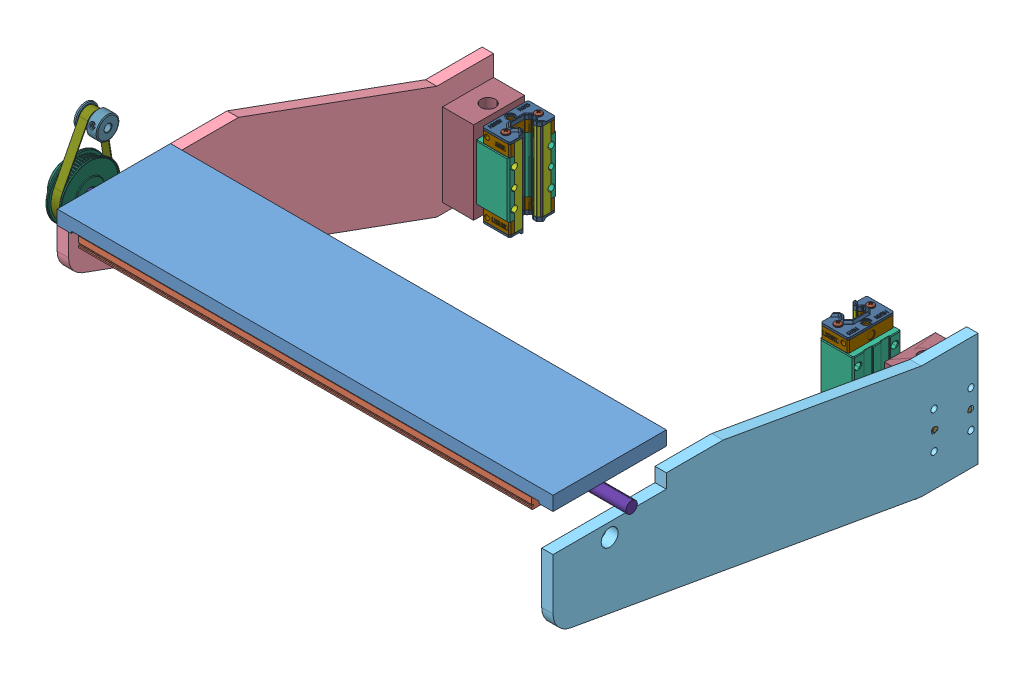
SolidWorks assembly Copia de Eje_X^Fresa_190502_2022, configuration Predeterminado. Lengths in mm.
Overall size (400 162.38 300).
39 component instances, 17 part files, 36 mates.
Components (placement in the parent):
- Puente_X-1: Puente_X [Predeterminado] at (-189.2038 15.372 -72.2278) x (1 0 0) z (0 -1 0) size (350 80 10)
- Rail_sup-1: Rail_sup [Predeterminado] at (-104.2038 2.9226 1.7722) x (0 0 1) z (1 0 0) size (12 8.1 320)
- Rail_Inf-1: Rail_Inf [Predeterminado] at (75.7962 2.9226 -66.2278) x (0 0 -1) z (-1 0 0) size (12 8.1 320)
-  Columa_xn-1:  Columa_xn [Predeterminado] at (-181.2038 -35.5839 -292.2278) x (0 -1 0) z (-1 0 0) size (130.96 300 8)
- Columa_xp-1: Columa_xp [Predeterminado] at (160.7962 -35.5839 -292.2278) x (0 -1 0) z (-1 0 0) size (130.96 300 8)
- HGH15CA-1: HGH15CA [Default] at (-131.2038 -79.3839 -274.2278) x (0 0 -1) z (0 1 0) size (34 23.7 61.49)
  - Copia de Copia de HGH15CA Block-1: Copia de Copia de HGH15CA Block [HGR15R300CE20] at origin size (34 23.7 39.4)
  - Copia de Copia de HGx15CA Retainer-1: Copia de Copia de HGx15CA Retainer [HGR15R300CE20] at origin size (26 4 55.4)
  - Copia de Copia de HGx15CA Tiny Red-1: Copia de Copia de HGx15CA Tiny Red [HGR15R300CE20] at origin size (14.2 1 55.4)
  - Copia de Copia de HGx15CA End Cap-1: Copia de Copia de HGx15CA End Cap [HGR15R300CE20] at origin size (32.5 19.5 8)
  - Copia de Copia de HGx15CA End Cap-2: Copia de Copia de HGx15CA End Cap [HGR15R300CE20] x (-1 0 0) z (0 0 -1) size (32.5 19.5 8)
  - Copia de Copia de HGx15CA Seal-1: Copia de Copia de HGx15CA Seal [HGR15R300CE20] at origin size (32.5 19.5 3)
  - Copia de Copia de HGx15CA Seal-2: Copia de Copia de HGx15CA Seal [HGR15R300CE20] x (-1 0 0) z (0 0 -1) size (32.5 19.5 3)
  - pan head cross recess screw_isog-1: pan head cross recess screw_isog [ISO 7045 - M2.5 x 16 - Z - 16C] at (11.5 11.8 30.8) x (0 0 -1) z (0 -1 0) size (18.05 5 5)
  - pan head cross recess screw_isog-2: pan head cross recess screw_isog [ISO 7045 - M2.5 x 16 - Z - 16C] at (-11.5 11.8 30.8) x (0 0 -1) z (0 1 0) size (18.05 5 5)
  - pan head cross recess screw_isog-3: pan head cross recess screw_isog [ISO 7045 - M2.5 x 16 - Z - 16C] at (11.5 11.8 -30.8) x (0 0 1) z (0 -1 0) size (18.05 5 5)
  - pan head cross recess screw_isog-4: pan head cross recess screw_isog [ISO 7045 - M2.5 x 16 - Z - 16C] at (-11.5 11.8 -30.8) x (0 0 1) z (0 1 0) size (18.05 5 5)
- HGH15CA-2: HGH15CA [Default] at (79.6902 -79.3839 -274.2278) x (0 0 -1) z (0 -1 0) size (34 23.7 61.49)
  - Copia de Copia de HGH15CA Block-1: Copia de Copia de HGH15CA Block [HGR15R300CE20] at origin size (34 23.7 39.4)
  - Copia de Copia de HGx15CA Retainer-1: Copia de Copia de HGx15CA Retainer [HGR15R300CE20] at origin size (26 4 55.4)
  - Copia de Copia de HGx15CA Tiny Red-1: Copia de Copia de HGx15CA Tiny Red [HGR15R300CE20] at origin size (14.2 1 55.4)
  - Copia de Copia de HGx15CA End Cap-1: Copia de Copia de HGx15CA End Cap [HGR15R300CE20] at origin size (32.5 19.5 8)
  - Copia de Copia de HGx15CA End Cap-2: Copia de Copia de HGx15CA End Cap [HGR15R300CE20] x (-1 0 0) z (0 0 -1) size (32.5 19.5 8)
  - Copia de Copia de HGx15CA Seal-1: Copia de Copia de HGx15CA Seal [HGR15R300CE20] at origin size (32.5 19.5 3)
  - Copia de Copia de HGx15CA Seal-2: Copia de Copia de HGx15CA Seal [HGR15R300CE20] x (-1 0 0) z (0 0 -1) size (32.5 19.5 3)
  - pan head cross recess screw_isog-1: pan head cross recess screw_isog [ISO 7045 - M2.5 x 16 - Z - 16C] at (11.5 11.8 30.8) x (0 0 -1) z (0 -1 0) size (18.05 5 5)
  - pan head cross recess screw_isog-2: pan head cross recess screw_isog [ISO 7045 - M2.5 x 16 - Z - 16C] at (-11.5 11.8 30.8) x (0 0 -1) z (0 1 0) size (18.05 5 5)
  - pan head cross recess screw_isog-3: pan head cross recess screw_isog [ISO 7045 - M2.5 x 16 - Z - 16C] at (11.5 11.8 -30.8) x (0 0 1) z (0 -1 0) size (18.05 5 5)
  - pan head cross recess screw_isog-4: pan head cross recess screw_isog [ISO 7045 - M2.5 x 16 - Z - 16C] at (-11.5 11.8 -30.8) x (0 0 1) z (0 1 0) size (18.05 5 5)
- guia_4x20-1: guia_4x20 [Predeterminado] at (-169.2038 -79.3839 -262.2278) x (0 0 1) z (-1 0 0) size (4 4 20)
- guia_4x20-2: guia_4x20 [Predeterminado] at (-169.2038 -79.3839 -286.2278) x (0 0 1) z (-1 0 0) size (4 4 20)
- guia_4x20-3: guia_4x20 [Predeterminado] at (140.7962 -79.3839 -262.2278) x (0 -0.924225 -0.381849) z (1 0 0) size (4 4 20)
- guia_4x20-4: guia_4x20 [Predeterminado] at (140.7962 -79.3839 -286.2278) x (0 -0.305624 0.952152) z (1 0 0) size (4 4 20)
- Soporte_tuerca_husillo_X-2: Soporte_tuerca_husillo_X [Predeterminado] at (130.7962 -50.1839 -256.2278) x (0 -1 0) z (1 0 0) size (58.4 36 22)
- Soporte_tuerca_husillo_X-1: Soporte_tuerca_husillo_X [Predeterminado] at (-159.2038 -108.5839 -256.2278) x (0 1 0) z (-1 0 0) size (58.4 36 22)
- GT2_20Tc-2: GT2_20Tc [Конфигурация1] at (-199.7261 36.3557 -38.7137) x (-1 0 0) z (0 0.380598 0.924741) size (16 16 16)
- GT2_60T-1: GT2_60T [Default] at (-216.1761 -4.128 -32.2278) x (0 0 1) z (1 0 0) size (42 42 18)
- Correa_158-1: Correa_158 [Predeterminado] at (-214.1761 -4.128 -32.2278) x (0 0.987408 -0.158192) z (1 0 0) size (66.95 38.7 6)
- Husillo-1: Husillo [Predeterminado] at (176.3239 -4.128 -32.2278) x (0 0 1) z (-1 0 0) size (8 8 400)
Mates (geometry in assembly coordinates):
- Coincidente8: coincident aligned: plane of Puente_X-1 through (-189.2038 5.372 7.7722) normal (-1 0 0); plane of  Columa_xn-1 through (-189.2038 -10.4485 -7.2278) normal (-1 0 0)
- Coincidente9: coincident anti-aligned: plane of Puente_X-1 through (-189.2038 5.372 -72.2278) normal (0 -1 0); plane of  Columa_xn-1 through (-189.2038 5.372 7.7722) normal (0 1 0)
- Coincidente10: coincident anti-aligned: plane of Puente_X-1 through (160.7962 5.372 -72.2278) normal (0 0 -1); plane of  Columa_xn-1 through (-189.2038 15.372 -72.2278) normal (0 0 1)
- Coincidente11: coincident aligned: plane of Puente_X-1 through (160.7962 5.372 7.7722) normal (1 0 0); plane of Columa_xp-1 through (160.7962 -10.4485 -7.2278) normal (1 0 0)
- Coincidente12: coincident anti-aligned: plane of Puente_X-1 through (160.7962 5.372 -72.2278) normal (0 0 -1); plane of Columa_xp-1 through (152.7962 15.372 -72.2278) normal (0 0 1)
- Coincidente13: coincident anti-aligned: plane of Puente_X-1 through (-189.2038 5.372 -72.2278) normal (0 -1 0); plane of Columa_xp-1 through (152.7962 5.372 7.7722) normal (0 1 0)
- Coincidente16: coincident aligned: plane of Puente_X-1 through (160.7962 5.372 7.7722) normal (0 0 1); plane of Rail_sup-1 through (145.7962 6.872 7.7722) normal (0 0 1)
- Coincidente32: coincident aligned: plane of Puente_X-1 through (160.7962 5.372 -72.2278) normal (0 0 -1); plane of Rail_Inf-1 through (-174.2038 6.872 -72.2278) normal (0 0 -1)
- Coincidente42: coincident anti-aligned: plane of  Columa_xn-1 through (-181.2038 -10.4485 -7.2278) normal (1 0 0); plane of Soporte_tuerca_husillo_X-1 through (-181.2038 -108.5839 -256.2278) normal (-1 0 0)
- Distancia10: distance = 7 mm aligned: plane of Soporte_tuerca_husillo_X-1 through (-181.2038 -108.5839 -256.2278) normal (0 -1 0); plane of  Columa_xn-1 through (-189.2038 -115.5839 -292.2278) normal (0 -1 0)
- Coincidente44: coincident aligned: plane of  Columa_xn-1 through (-189.2038 -35.5839 -292.2278) normal (0 0 -1); plane of Soporte_tuerca_husillo_X-1 through (-181.2038 -108.5839 -292.2278) normal (0 0 -1)
- Coincidente45: coincident anti-aligned: plane of HGH15CA-1/Copia de Copia de HGH15CA Block-1 through (-159.2038 -59.6839 -290.2278) normal (-1 0 0); plane of Soporte_tuerca_husillo_X-1 through (-159.2038 -108.5839 -256.2278) normal (1 0 0)
- Distancia11: distance = 1 mm aligned: plane of HGH15CA-1/Copia de Copia de HGH15CA Block-1 through (-136.5038 -59.6839 -291.2278) normal (0 0 -1); plane of Soporte_tuerca_husillo_X-1 through (-181.2038 -108.5839 -292.2278) normal (0 0 -1)
- Coincidente47: coincident aligned: plane of HGH15CA-1/Copia de Copia de HGx15CA Seal-2 through (-137.6195 -108.5839 -279.3778) normal (0 -1 0); plane of Soporte_tuerca_husillo_X-1 through (-181.2038 -108.5839 -256.2278) normal (0 -1 0)
- Concéntrica7: concentric anti-aligned: cylinder of  Columa_xn-1 through (-189.2038 -79.3839 -262.2278) axis (-1 0 0) radius 2; cylinder of guia_4x20-1 through (-189.2038 -79.3839 -262.2278) axis (1 0 0) radius 2
- Coincidente48: coincident aligned: plane of  Columa_xn-1 through (-189.2038 -10.4485 -7.2278) normal (-1 0 0); plane of guia_4x20-1 through (-189.2038 -79.3839 -262.2278) normal (-1 0 0)
- Coincidente49: coincident aligned: plane of  Columa_xn-1 through (-189.2038 -10.4485 -7.2278) normal (-1 0 0); plane of guia_4x20-2 through (-189.2038 -79.3839 -286.2278) normal (-1 0 0)
- Concéntrica8: concentric anti-aligned: cylinder of  Columa_xn-1 through (-189.2038 -79.3839 -286.2278) axis (-1 0 0) radius 2; cylinder of guia_4x20-2 through (-189.2038 -79.3839 -286.2278) axis (1 0 0) radius 2
- Concéntrica9: concentric anti-aligned: cylinder of Correa_158-1 through (-208.1761 -4.128 -32.2278) axis (-1 0 0) radius 18.85; cylinder of GT2_60T-1 through (-223.6761 -4.128 -32.2278) axis (1 0 0) radius 12.5
- Distancia12: distance = 1 mm anti-aligned: plane of Correa_158-1 through (-208.1761 -4.128 -32.2278) normal (1 0 0); plane of GT2_60T-1 through (-207.1761 -4.128 -32.2278) normal (-1 0 0)
- Concéntrica10: concentric anti-aligned: cylinder of GT2_20Tc-2 through (-199.7261 36.3557 -38.7137) axis (1 0 0) radius 8; cylinder of Correa_158-1 through (-208.1761 36.3557 -38.7137) axis (-1 0 0) radius 6.1
- Distancia13: distance = 1 mm anti-aligned: plane of Correa_158-1 through (-208.1761 -4.128 -32.2278) normal (1 0 0); plane of GT2_20Tc-2 through (-207.1761 36.3557 -38.7137) normal (-1 0 0)
- Coincidente50: coincident anti-aligned: plane of Columa_xp-1 through (152.7962 -10.4485 -7.2278) normal (-1 0 0); plane of Soporte_tuerca_husillo_X-2 through (152.7962 -50.1839 -256.2278) normal (1 0 0)
- Coincidente51: coincident aligned: plane of Columa_xp-1 through (152.7962 -35.5839 -292.2278) normal (0 0 -1); plane of Soporte_tuerca_husillo_X-2 through (152.7962 -50.1839 -292.2278) normal (0 0 -1)
- Distancia14: distance = 7 mm aligned: plane of Soporte_tuerca_husillo_X-2 through (152.7962 -108.5839 -256.2278) normal (0 -1 0); plane of Columa_xp-1 through (152.7962 -115.5839 -292.2278) normal (0 -1 0)
- Distancia15: distance = 1 mm aligned: plane of HGH15CA-2/Copia de Copia de HGH15CA Block-1 through (84.9902 -99.0839 -291.2278) normal (0 0 -1); plane of Soporte_tuerca_husillo_X-2 through (152.7962 -50.1839 -292.2278) normal (0 0 -1)
- Coincidente55: coincident aligned: plane of HGH15CA-2/Copia de Copia de HGx15CA Seal-1 through (86.1059 -108.5839 -269.0778) normal (0 -1 0); plane of Soporte_tuerca_husillo_X-2 through (152.7962 -108.5839 -256.2278) normal (0 -1 0)
- Coincidente56: coincident aligned: plane of Columa_xp-1 through (160.7962 -10.4485 -7.2278) normal (1 0 0); plane of guia_4x20-3 through (160.7962 -79.3839 -262.2278) normal (1 0 0)
- Concéntrica11: concentric aligned: circle of Columa_xp-1; circle of guia_4x20-4
- Concéntrica12: concentric anti-aligned: cylinder of Columa_xp-1 through (160.7962 -79.3839 -262.2278) axis (1 0 0) radius 2; cylinder of guia_4x20-3 through (160.7962 -79.3839 -262.2278) axis (-1 0 0) radius 2
- Coincidente57: coincident aligned: plane of Columa_xp-1 through (160.7962 -10.4485 -7.2278) normal (1 0 0); plane of guia_4x20-4 through (160.7962 -79.3839 -286.2278) normal (1 0 0)
- Concéntrica13: concentric anti-aligned: cylinder of GT2_60T-1 through (-186.1761 -4.128 -32.2278) axis (-1 0 0) radius 4; cylinder of Husillo-1 through (-223.6761 -4.128 -32.2278) axis (1 0 0) radius 4
- Paralelo1: parallel aligned: plane of GT2_60T-1 through (-219.9261 -4.128 -19.2278) normal (0 0 1); plane of Husillo-1 through (-213.6761 -0.128 -29.2278) normal (0 0 1)
- Concéntrica14: concentric aligned: cylinder of  Columa_xn-1 through (-189.2038 -4.128 -32.2278) axis (1 0 0) radius 6; cylinder of Husillo-1 through (-223.6761 -4.128 -32.2278) axis (1 0 0) radius 4
- Coincidente59: coincident aligned: plane of GT2_60T-1 through (-223.6761 -4.128 -32.2278) normal (-1 0 0); plane of Husillo-1 through (-223.6761 -4.128 -32.2278) normal (-1 0 0)
- Paralelo2: parallel aligned: plane of  Columa_xn-1 through (-189.2038 5.372 7.7722) normal (0 0 1); plane of GT2_60T-1 through (-219.9261 -4.128 -19.2278) normal (0 0 1)
